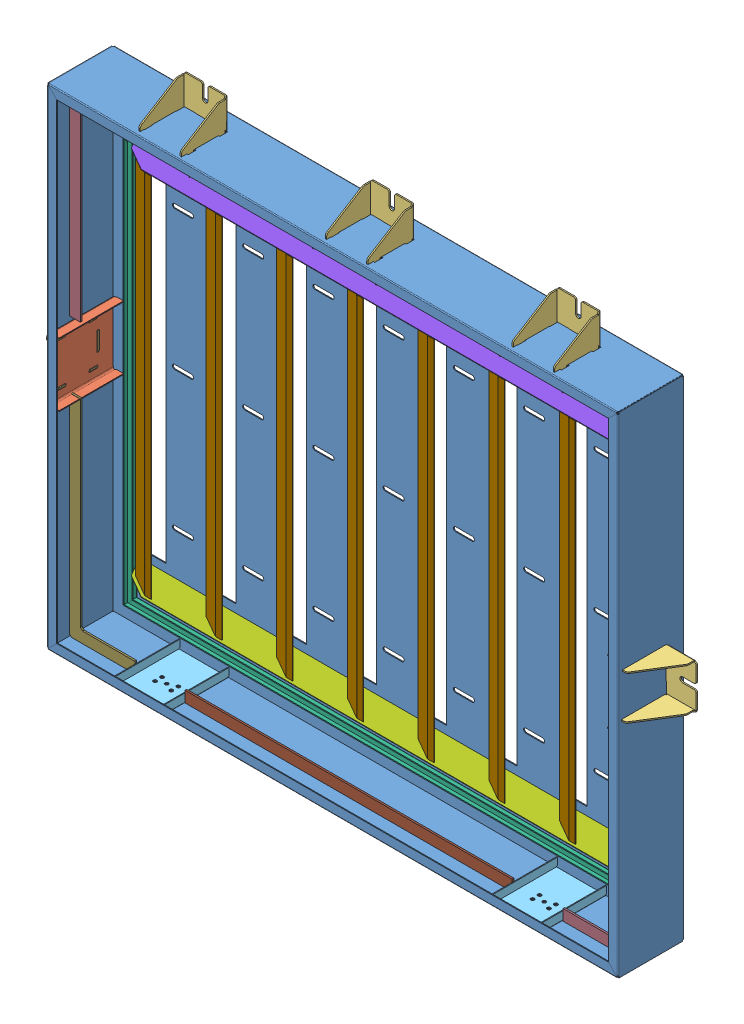
SolidWorks assembly 門蓋組, configuration 預設. Lengths in mm.
Overall size (1436.55 1191.37 161.57).
35 component instances, 15 part files, 62 mates.
Components (placement in the parent):
- LB-A54A-02-13-1: LB-A54A-02-13 [預設] at (-970.643 -646.3034 -75.3) size (1300.6 1116.4 150.6)
- FE2100LZ-54-45-1: FE2100LZ-54-45 [預設] at (-470.443 632.9966 -73.4) x (0 0 1) z (0 -1 0) size (146.8 145.3 23.65)
- FE2100LZ-54-47-1: FE2100LZ-54-47 [預設] at (-704.373 628.9966 -37.75) size (99.93 73.97 105.55)
- FE2100LZ-54-47-2: FE2100LZ-54-47 [預設] at (-279.373 628.9966 -37.75) size (99.93 73.97 105.55)
- FE2100LZ-54-47-3: FE2100LZ-54-47 [預設] at (145.627 628.9966 -37.75) size (99.93 73.97 105.55)
- FE2100LZ-54-45-2: FE2100LZ-54-45 [預設] at (-45.443 632.9966 -73.4) x (0 0 1) z (0 -1 0) size (146.8 145.3 23.65)
- FE2100LZ-54-45-3: FE2100LZ-54-45 [預設] at (379.557 632.9966 -73.4) x (0 0 1) z (0 -1 0) size (146.8 145.3 23.65)
- FE2100LZ-54-45-4: FE2100LZ-54-45 [預設] at (492.857 -13.6034 -73.4193) x (0 0 1) z (-1 0 0) size (146.8 145.3 23.65)
- FE2100LZ-54-47-4: FE2100LZ-54-47 [預設] at (488.857 220.3266 -37.7693) x (0 -1 0) z (0 0 1) size (99.93 73.97 105.55)
- FE2100LZ-54-45-5: FE2100LZ-54-45 [預設] at (-803.743 156.3966 -73.4193) x (0 0 1) z (1 0 0) size (146.8 145.3 23.65)
- FE2100LZ-54-47-5: FE2100LZ-54-47 [預設] at (-799.743 -74.3534 -37.7693) x (0 1 0) z (0 0 1) size (99.93 73.97 105.55)
- FE2100LZ-54-44-1: FE2100LZ-54-44 [預設] at (-627.493 -488.4034 35.05) x (1 0 0) z (0 1 0) size (61 40 7)
- FE2100LZ-54-46-1: FE2100LZ-54-46 [預設] at (-669.993 -479.4034 -73.25) x (0 0 1) z (0 1 0) size (146.5 113.8 19.9)
- FE2100LZ-54-44-2: FE2100LZ-54-44 [預設] at (232.507 -488.4034 35.05) x (1 0 0) z (0 1 0) size (61 40 7)
- FE2100LZ-54-46-2: FE2100LZ-54-46 [預設] at (190.007 -479.4034 -73.25) x (0 0 1) z (0 1 0) size (146.5 113.8 19.9)
- 門蓋補強框-1: 門蓋補強框 [預設] at (-142.038 49.5383 -68.2367) size (1233.23 1037.93 10.13)
  - LB-A54A-02-14-1: LB-A54A-02-14 [預設] at (-1662.9116 513.3252 -5.0633) size (1230.93 1037.93 10.13)
  - LB-A54A-02-14-2: LB-A54A-02-14 [預設] at (1638.3282 -467.6819 -5.0633) x (-1 0 0) z (0 0 1) size (1230.93 1037.93 10.13)
- FE2100LZ-54-29-1: FE2100LZ-54-29 [預設] at (-93656.2844 -344.3034 22133.659) x (1 0 0) z (0 -1 0) size (1171.28 75.4 1.2)
- FE2100LZ-54-30-1: FE2100LZ-54-30 [預設] at (-95338.7558 497.8966 -22231.8692) x (1 0 0) z (0 1 0) size (1171.28 75.4 1.2)
- FE2100LZ-54-27-1: FE2100LZ-54-27 [預設] at (-650.3431 490.6966 3.1078) x (0 -1 0) z (0.5 0 -0.866025) size (835 123.62 23.67)
- FE2100LZ-54-27-2: FE2100LZ-54-27 [預設] at (-489.3431 490.6966 3.1078) x (0 -1 0) z (0.5 0 -0.866025) size (835 123.62 23.67)
- FE2100LZ-54-27-3: FE2100LZ-54-27 [預設] at (-328.3431 490.6966 3.1078) x (0 -1 0) z (0.5 0 -0.866025) size (835 123.62 23.67)
- FE2100LZ-54-27-4: FE2100LZ-54-27 [預設] at (-167.3431 490.6966 3.1078) x (0 -1 0) z (0.5 0 -0.866025) size (835 123.62 23.67)
- FE2100LZ-54-27-5: FE2100LZ-54-27 [預設] at (-6.3431 490.6966 3.1078) x (0 -1 0) z (0.5 0 -0.866025) size (835 123.62 23.67)
- FE2100LZ-54-27-6: FE2100LZ-54-27 [預設] at (154.6569 490.6966 3.1078) x (0 -1 0) z (0.5 0 -0.866025) size (835 123.62 23.67)
- FE2100LZ-54-27-7: FE2100LZ-54-27 [預設] at (315.6569 490.6966 3.1078) x (0 -1 0) z (0.5 0 -0.866025) size (835 123.62 23.67)
- FE2100LZ-54-28-1: FE2100LZ-54-28 [預設] at (366.448 490.6966 -85.3637) x (0 -1 0) z (-0.866025 0 0.5) size (835 94.52 26.54)
- LB-A54A-02-38-1: LB-A54A-02-38 [預設] at (-97123.894 21912.3268 22.5) size (745 25 4)
- LB-A54A-02-42-1: LB-A54A-02-42 [預設] at (21575.3315 100651.057 22.5) x (0 -1 0) z (0 0 1) size (480.5 149.05 4)
- LB-A54A-02-41-1: LB-A54A-02-41 [預設] at (22757.0388 99507.9227 22.5) x (0 -1 0) z (0 0 1) size (480.5 171.95 4)
- LB-A54A-02-39-1: LB-A54A-02-39 [預設] at (-98169.6355 23115.0249 22.5) size (286 25 4)
- LB-A54A-02-39-2: LB-A54A-02-39 [預設] at (-97750.9355 23115.0249 22.5) size (286 25 4)
- LB-A54A-02-40-1: LB-A54A-02-40 [預設] at (22767.5939 99075.3728 22.5) x (0 -1 0) z (0 0 1) size (491.4 128.4 4)
- LB-A54A-02-41-2: LB-A54A-02-41 [預設] at (-23067.9248 -99354.3294 22.5) x (0 1 0) z (0 0 1) size (480.5 171.95 4)
Mates (geometry in assembly coordinates):
- 重合/共線/共點1: coincident anti-aligned: plane of LB-A54A-02-13-1 through (-803.843 632.9966 -1186) normal (0 -1 0); plane of FE2100LZ-54-45-1 through (-622.443 632.9966 -73.4) normal (0 1 0)
- 重合/共線/共點2: coincident aligned: plane of LB-A54A-02-13-1 through (-534.693 632.9966 -37.75) normal (0 0 1); plane of FE2100LZ-54-45-1 through (-534.693 630.9966 -37.75) normal (0 0 1)
- 重合/共線/共點3: coincident aligned: plane of LB-A54A-02-13-1 through (-606.993 632.9966 37.4) normal (1 0 0); plane of FE2100LZ-54-45-1 through (-606.993 630.9966 37.4) normal (1 0 0)
- 重合/共線/共點4: coincident anti-aligned: plane of LB-A54A-02-13-1 through (-803.843 634.9966 -1186) normal (0 1 0); plane of FE2100LZ-54-47-1 through (-603.993 634.9966 37.97) normal (0 -1 0)
- 重合/共線/共點5: coincident anti-aligned: plane of LB-A54A-02-13-1 through (-534.693 632.9966 -37.75) normal (0 0 1); plane of FE2100LZ-54-47-1 through (-414.973 640.5512 -37.75) normal (0 0 -1)
- 重合/共線/共點6: coincident anti-aligned: plane of LB-A54A-02-13-1 through (-606.993 632.9966 37.4) normal (1 0 0); plane of FE2100LZ-54-47-1 through (-606.993 640.5512 -224.33) normal (-1 0 0)
- 重合/共線/共點7: coincident aligned: plane of LB-A54A-02-13-1 through (492.857 50.6466 -37.7693) normal (0 0 1); plane of FE2100LZ-54-45-4 through (490.857 50.6466 -37.7693) normal (0 0 1)
- 重合/共線/共點8: coincident anti-aligned: plane of LB-A54A-02-13-1 through (492.857 -479.5034 -1370.2) normal (-1 0 0); plane of FE2100LZ-54-45-4 through (492.857 138.3966 -73.4193) normal (1 0 0)
- 重合/共線/共點9: coincident aligned: plane of LB-A54A-02-13-1 through (492.857 19.8466 55.4807) normal (0 1 0); plane of FE2100LZ-54-45-4 through (490.857 19.8466 55.4807) normal (0 1 0)
- 重合/共線/共點10: coincident anti-aligned: plane of LB-A54A-02-13-1 through (494.857 -479.5034 -1370.2) normal (1 0 0); plane of FE2100LZ-54-47-4 through (494.857 119.9466 37.9507) normal (-1 0 0)
- 重合/共線/共點11: coincident anti-aligned: plane of LB-A54A-02-13-1 through (492.857 122.9466 37.3807) normal (0 -1 0); plane of FE2100LZ-54-47-4 through (500.4115 122.9466 -224.3493) normal (0 1 0)
- 重合/共線/共點12: coincident anti-aligned: plane of LB-A54A-02-13-1 through (492.857 50.6466 -37.7693) normal (0 0 1); plane of FE2100LZ-54-47-4 through (500.4115 -69.0734 -37.7693) normal (0 0 -1)
- 重合/共線/共點13: coincident anti-aligned: plane of LB-A54A-02-13-1 through (-803.743 -479.5034 -73.4) normal (1 0 0); plane of FE2100LZ-54-45-5 through (-803.743 4.3966 -73.4193) normal (-1 0 0)
- 重合/共線/共點14: coincident aligned: plane of LB-A54A-02-13-1 through (-803.743 92.1466 -37.7693) normal (0 0 1); plane of FE2100LZ-54-45-5 through (-801.743 92.1466 -37.7693) normal (0 0 1)
- 重合/共線/共點15: coincident aligned: plane of LB-A54A-02-13-1 through (-803.743 122.9466 55.4807) normal (0 -1 0); plane of FE2100LZ-54-45-5 through (-801.743 122.9466 55.4807) normal (0 -1 0)
- 重合/共線/共點16: coincident anti-aligned: plane of LB-A54A-02-13-1 through (-803.743 92.1466 -37.7693) normal (0 0 1); plane of FE2100LZ-54-47-5 through (-811.2975 215.0466 -37.7693) normal (0 0 -1)
- 重合/共線/共點17: coincident anti-aligned: plane of LB-A54A-02-13-1 through (-805.743 -479.5034 -73.4) normal (-1 0 0); plane of FE2100LZ-54-47-5 through (-805.743 94.8466 -34.7693) normal (1 0 0)
- 重合/共線/共點18: coincident anti-aligned: plane of LB-A54A-02-13-1 through (-803.743 122.9466 55.4807) normal (0 -1 0); plane of FE2100LZ-54-47-5 through (-811.2975 122.9466 59.7707) normal (0 1 0)
- 重合/共線/共點20: coincident anti-aligned: plane of LB-A54A-02-13-1 through (-803.843 -481.4034 -73.4) normal (0 -1 0); plane of FE2100LZ-54-44-1 through (-569.493 -481.4034 -1.95) normal (0 1 0)
- 同軸心2: concentric aligned: cylinder of LB-A54A-02-13-1 through (-615.493 -479.4034 19.55) axis (0 -1 0) radius 4; cylinder of FE2100LZ-54-44-1 through (-615.493 -481.4034 19.55) axis (0 -1 0) radius 2.65
- 同軸心3: concentric aligned: cylinder of LB-A54A-02-13-1 through (-615.493 -479.4034 3.55) axis (0 -1 0) radius 4; cylinder of FE2100LZ-54-44-1 through (-615.493 -481.4034 3.55) axis (0 -1 0) radius 2.65
- 重合/共線/共點21: coincident anti-aligned: plane of LB-A54A-02-13-1 through (-803.843 -479.4034 -73.4) normal (0 1 0); plane of FE2100LZ-54-46-1 through (-541.993 -479.4034 -73.25) normal (0 -1 0)
- 同軸心4: concentric aligned: cylinder of LB-A54A-02-13-1 through (-596.993 -479.4034 11.55) axis (0 -1 0) radius 4; cylinder of FE2100LZ-54-46-1 through (-596.993 -477.4034 11.55) axis (0 -1 0) radius 4
- 同軸心5: concentric aligned: cylinder of LB-A54A-02-13-1 through (-615.493 -479.4034 19.55) axis (0 -1 0) radius 4; cylinder of FE2100LZ-54-46-1 through (-615.493 -477.4034 19.55) axis (0 -1 0) radius 4
- 重合/共線/共點22: coincident anti-aligned: plane of LB-A54A-02-13-1 through (-803.843 -479.5034 -73.3) normal (0 0 1); plane of 門蓋補強框-1/LB-A54A-02-14-1 through (-768.783 591.5632 -73.3) normal (0 0 -1)
- 平行相距1: distance = 32.8 mm anti-aligned: plane of 門蓋補強框-1/LB-A54A-02-14-2 through (458.1236 -446.6034 -71.54) normal (0 -1 0); plane of LB-A54A-02-13-1 through (-803.843 -479.4034 -73.4) normal (0 1 0)
- 平行相距2: distance = 32.8 mm anti-aligned: plane of LB-A54A-02-13-1 through (-803.743 -479.5034 -73.4) normal (1 0 0); plane of 門蓋補強框-1/LB-A54A-02-14-1 through (-770.943 591.5632 -71.54) normal (-1 0 0)
- 重合/共線/共點28: coincident anti-aligned: plane of LB-A54A-02-13-1 through (-803.843 -479.5034 -73.3) normal (0 0 1); plane of FE2100LZ-54-29-1 through (387.7202 -345.5034 -73.3) normal (0 0 -1)
- 平行相距5: distance = 133.9 mm anti-aligned: plane of LB-A54A-02-13-1 through (-803.843 -479.4034 -73.4) normal (0 1 0); plane of FE2100LZ-54-29-1 through (422.5942 -345.5034 -2.8965) normal (0 -1 0)
- 平行相距6: distance = 5 mm: plane of 門蓋補強框-1/LB-A54A-02-14-1 through (-748.6898 591.5632 -89.4732) normal (1 0 0); point of FE2100LZ-54-29-1
- 重合/共線/共點31: coincident anti-aligned: plane of LB-A54A-02-13-1 through (-803.843 -479.5034 -73.3) normal (0 0 1); plane of FE2100LZ-54-30-1 through (387.7202 499.0966 -73.3) normal (0 0 -1)
- 平行相距7: distance = 133.9 mm anti-aligned: plane of FE2100LZ-54-30-1 through (422.5942 499.0966 -2.8965) normal (0 1 0); plane of LB-A54A-02-13-1 through (-803.843 632.9966 -1186) normal (0 -1 0)
- 平行相距8: distance = 5 mm: point of FE2100LZ-54-30-1; plane of 門蓋補強框-1/LB-A54A-02-14-1 through (-748.6898 591.5632 -89.4732) normal (1 0 0)
- 重合/共線/共點34: coincident anti-aligned: plane of LB-A54A-02-13-1 through (-803.843 -479.5034 -73.3) normal (0 0 1); plane of FE2100LZ-54-27-1 through (-618.6998 490.6966 -73.3) normal (0 0 -1)
- 重合/共線/共點35: coincident anti-aligned: plane of FE2100LZ-54-29-1 through (422.5942 -344.3034 -2.8965) normal (0 1 0); plane of FE2100LZ-54-27-1 through (-750.6784 -344.3034 -73.3) normal (0 -1 0)
- 重合/共線/共點36: coincident: point of FE2100LZ-54-29-1; plane of FE2100LZ-54-27-1 through (-647.9369 490.6966 -5.2064) normal (1 0 0)
- 重合/共線/共點37: coincident anti-aligned: plane of LB-A54A-02-13-1 through (-803.843 -479.5034 -73.3) normal (0 0 1); plane of FE2100LZ-54-28-1 through (465.9048 490.6966 -73.3) normal (0 0 -1)
- 重合/共線/共點38: coincident anti-aligned: plane of FE2100LZ-54-29-1 through (422.5942 -344.3034 -2.8965) normal (0 1 0); plane of FE2100LZ-54-28-1 through (358.343 -344.3034 -72.1) normal (0 -1 0)
- 重合/共線/共點39: coincident: line of FE2100LZ-54-29-1 through (372.7202 -344.3034 -72.1) axis (0.5 0 0.866025); plane of FE2100LZ-54-28-1 through (419.1897 490.6966 8.3875) normal (-0.866025 0 0.5)
- 重合/共線/共點40: coincident anti-aligned: plane of LB-A54A-02-13-1 through (-803.843 -479.4034 -73.4) normal (0 1 0); plane of LB-A54A-02-38-1 through (-540.093 -479.4034 26.5) normal (0 -1 0)
- 重合/共線/共點41: coincident anti-aligned: plane of FE2100LZ-54-46-1 through (-540.093 -477.5034 -73.25) normal (1 0 0); plane of LB-A54A-02-38-1 through (-540.093 -454.4034 26.5) normal (-1 0 0)
- 平行相距9: distance = 46.8 mm: plane of LB-A54A-02-38-1 through (-540.093 -479.4034 26.5) normal (0 0 1); line of LB-A54A-02-13-1 through (-783.843 -459.5034 73.3) axis (1 0 0)
- 重合/共線/共點43: coincident anti-aligned: plane of LB-A54A-02-13-1 through (-803.843 -479.4034 -73.4) normal (0 1 0); plane of LB-A54A-02-42-1 through (-798.743 -479.4034 26.5) normal (0 -1 0)
- 平行相距10: distance = 46.8 mm: line of LB-A54A-02-13-1 through (-783.843 613.0966 73.3) axis (0 -1 0); plane of LB-A54A-02-42-1 through (-778.743 1.0966 26.5) normal (0 0 1)
- 重合/共線/共點45: coincident anti-aligned: plane of LB-A54A-02-13-1 through (-803.743 -479.5034 -73.4) normal (1 0 0); plane of LB-A54A-02-42-1 through (-803.743 1.0966 26.5) normal (-1 0 0)
- 重合/共線/共點46: coincident anti-aligned: plane of LB-A54A-02-13-1 through (-803.843 -479.4034 -73.4) normal (0 1 0); plane of LB-A54A-02-41-1 through (320.907 -479.4034 26.5) normal (0 -1 0)
- 重合/共線/共點47: coincident anti-aligned: plane of LB-A54A-02-13-1 through (492.857 -479.5034 -1370.2) normal (-1 0 0); plane of LB-A54A-02-41-1 through (492.857 -474.4034 26.5) normal (1 0 0)
- 平行相距11: distance = 46.8 mm: plane of LB-A54A-02-41-1 through (320.907 -479.4034 26.5) normal (0 0 1); line of LB-A54A-02-13-1 through (472.957 -459.5034 73.3) axis (0 1 0)
- 重合/共線/共點49: coincident anti-aligned: plane of LB-A54A-02-13-1 through (-803.843 632.9966 -1186) normal (0 -1 0); plane of LB-A54A-02-39-1 through (-482.793 632.9966 26.5) normal (0 1 0)
- 平行相距12: distance = 46.8 mm: line of LB-A54A-02-13-1 through (472.957 613.0966 73.3) axis (-1 0 0); plane of LB-A54A-02-39-1 through (-482.793 607.9966 26.5) normal (0 0 1)
- 重合/共線/共點51: coincident anti-aligned: plane of FE2100LZ-54-45-1 through (-482.793 761.3466 -73.4) normal (1 0 0); plane of LB-A54A-02-39-1 through (-482.793 632.9966 26.5) normal (-1 0 0)
- 重合/共線/共點52: coincident anti-aligned: plane of LB-A54A-02-13-1 through (-803.843 632.9966 -1186) normal (0 -1 0); plane of LB-A54A-02-39-2 through (-64.093 632.9966 26.5) normal (0 1 0)
- 平行相距13: distance = 46.8 mm: plane of LB-A54A-02-39-2 through (-64.093 607.9966 26.5) normal (0 0 1); line of LB-A54A-02-13-1 through (472.957 613.0966 73.3) axis (-1 0 0)
- 重合/共線/共點55: coincident anti-aligned: plane of FE2100LZ-54-45-3 through (221.907 627.3466 -73.4) normal (-1 0 0); plane of LB-A54A-02-39-2 through (221.907 607.9966 26.5) normal (1 0 0)
- 重合/共線/共點56: coincident anti-aligned: plane of LB-A54A-02-13-1 through (-803.843 632.9966 -1186) normal (0 -1 0); plane of LB-A54A-02-40-1 through (487.857 632.9966 26.5) normal (0 1 0)
- 平行相距14: distance = 46.8 mm: plane of LB-A54A-02-40-1 through (492.857 141.5966 26.5) normal (0 0 1); line of LB-A54A-02-13-1 through (472.957 613.0966 73.3) axis (-1 0 0)
- 重合/共線/共點58: coincident anti-aligned: plane of LB-A54A-02-13-1 through (492.857 -479.5034 -1370.2) normal (-1 0 0); plane of LB-A54A-02-40-1 through (492.857 141.5966 26.5) normal (1 0 0)
- 重合/共線/共點59: coincident anti-aligned: plane of LB-A54A-02-13-1 through (-803.843 632.9966 -1186) normal (0 -1 0); plane of LB-A54A-02-41-2 through (-631.793 632.9966 26.5) normal (0 1 0)
- 重合/共線/共點60: coincident anti-aligned: plane of LB-A54A-02-13-1 through (-803.743 -479.5034 -73.4) normal (1 0 0); plane of LB-A54A-02-41-2 through (-803.743 627.9966 26.5) normal (-1 0 0)
- 平行相距15: distance = 46.8 mm: plane of LB-A54A-02-41-2 through (-631.793 632.9966 26.5) normal (0 0 1); line of LB-A54A-02-13-1 through (-783.843 613.0966 73.3) axis (0 -1 0)
- 局部直線複製2: unknown: line of LB-A54A-02-13-1 through (491.3601 -479.4034 -73.3) axis (-1 0 0)
- 局部直線複製3: unknown: line of LB-A54A-02-13-1 through (491.3601 -479.4034 -73.3) axis (-1 0 0)
